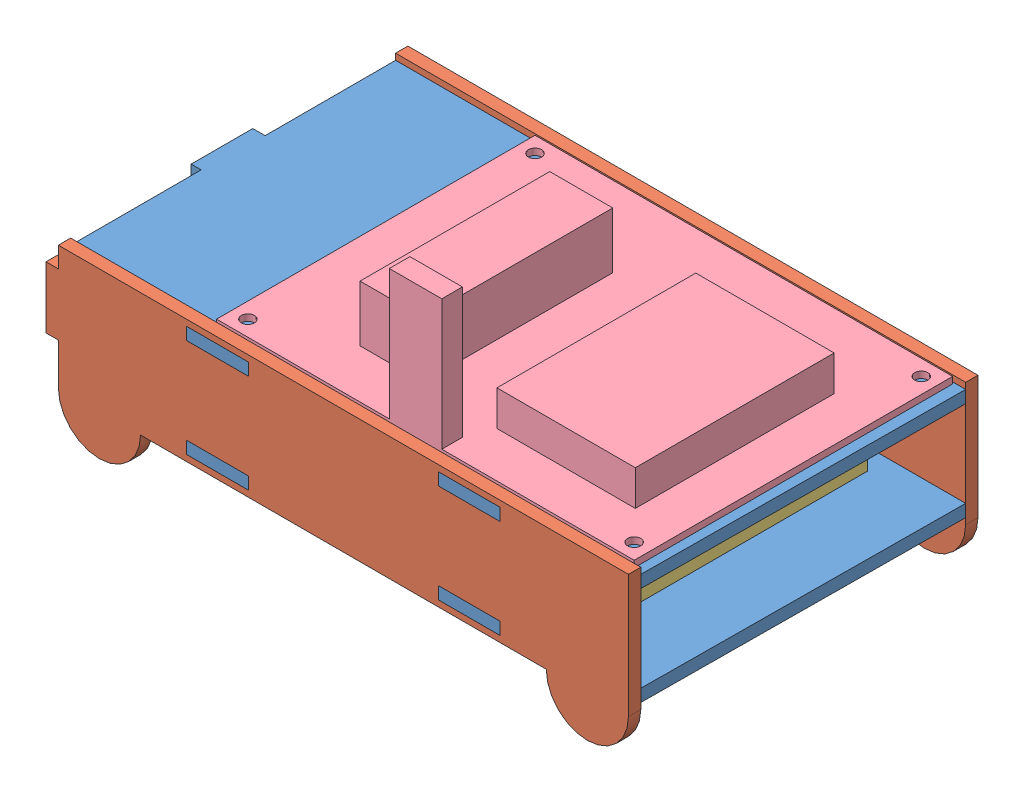
SolidWorks assembly Assem1, configuration Default. Lengths in mm.
Overall size (142.27 71.77 84.47).
6 component instances, 4 part files, 11 mates.
Components (placement in the parent):
- box_tb-1: box_tb [Default] at (-25.0585 97.1577 0.6543) x (1 0 0) z (0 -1 0) size (141.69 84.47 3)
- box_tb-2: box_tb [Default] at (-25.0585 73.1577 0.6543) x (1 0 0) z (0 -1 0) size (141.69 84.47 3)
- box_sides-1: box_sides [Default] at (-61.0504 59.6986 -9.3257) size (141.7 40 3)
- box_sides-2: box_sides [Default] at (-61.6164 59.6986 72.1443) size (141.7 40 3)
- batterypack-1: batterypack [Default] at (58.9177 73.1577 66.4872) size (64 18.86 67.65)
- carrierboard-1: carrierboard [Default] at (70.6755 97.1577 49.221) size (101.6 33.27 77.47)
Mates (geometry in assembly coordinates):
- Coincident1: coincident anti-aligned: plane of box_tb-2 through (-15.3764 70.1577 72.1443) normal (0 0 1); plane of box_sides-2 through (-51.6164 68.6577 72.1443) normal (0 0 -1)
- Coincident2: coincident anti-aligned: plane of box_tb-2 through (46.4196 70.1577 -6.3257) normal (0 0 -1); plane of box_sides-1 through (-51.0504 68.6577 -6.3257) normal (0 0 1)
- Coincident3: coincident anti-aligned: plane of box_tb-2 through (-25.0585 73.1577 0.6543) normal (0 1 0); plane of box_sides-2 through (-30.3764 73.1577 72.1443) normal (0 -1 0)
- Coincident4: coincident anti-aligned: plane of box_tb-2 through (45.8536 70.1577 75.1443) normal (1 0 0); plane of box_sides-2 through (45.8536 73.1577 72.1443) normal (-1 0 0)
- Coincident5: coincident anti-aligned: plane of box_tb-2 through (-25.0585 73.1577 0.6543) normal (0 1 0); plane of box_sides-1 through (-29.8104 73.1577 -9.3257) normal (0 -1 0)
- Coincident6: coincident anti-aligned: plane of box_tb-2 through (-14.8104 70.1577 -9.3257) normal (1 0 0); plane of box_sides-1 through (-14.8104 73.1577 -9.3257) normal (-1 0 0)
- Coincident7: coincident anti-aligned: plane of box_tb-1 through (-15.3764 94.1577 72.1443) normal (0 0 1); plane of box_sides-2 through (-51.6164 68.6577 72.1443) normal (0 0 -1)
- Coincident8: coincident anti-aligned: plane of box_tb-1 through (-25.0585 97.1577 0.6543) normal (0 1 0); plane of box_sides-2 through (-30.3764 97.1577 72.1443) normal (0 -1 0)
- Coincident9: coincident anti-aligned: plane of box_tb-1 through (-15.3764 94.1577 75.1443) normal (1 0 0); plane of box_sides-2 through (-15.3764 97.1577 72.1443) normal (-1 0 0)
- Coincident10: coincident anti-aligned: plane of box_tb-2 through (-25.0585 73.1577 0.6543) normal (0 1 0); plane of batterypack-1 through (58.9177 73.1577 66.4872) normal (0 -1 0)
- Coincident12: coincident anti-aligned: plane of box_tb-1 through (-25.0585 97.1577 0.6543) normal (0 1 0); plane of carrierboard-1 through (70.6755 97.1577 49.221) normal (0 -1 0)
